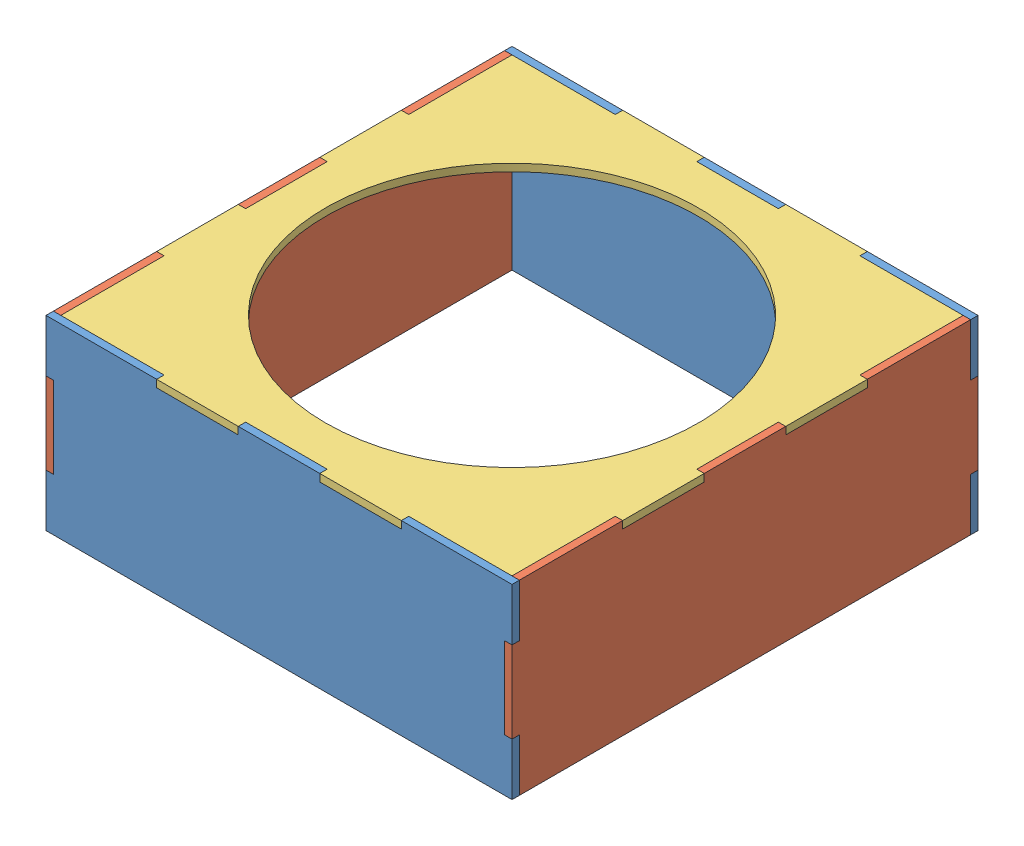
SolidWorks assembly ARM_BOX, configuration Défaut. Lengths in mm.
Overall size (200 80 200).
5 component instances, 3 part files, 13 mates.
Components (placement in the parent):
- BOX_SIDE2-1: BOX_SIDE2 [Défaut] at origin size (200 80 3.17)
- BOX_SIDE2-2: BOX_SIDE2 [Défaut] at (0 0 -196.825) size (200 80 3.17)
- BOX_SIDE1-1: BOX_SIDE1 [Défaut] at (96.825 0 -96.825) x (0 0 -1) z (1 0 0) size (200 80 3.17)
- BOX_SIDE1-2: BOX_SIDE1 [Défaut] at (-96.825 0 -96.825) x (0 0 1) z (-1 0 0) size (200 80 3.17)
- BOX_TOP-1: BOX_TOP [Défaut] at (0 36.825 -96.825) size (200 3.17 200)
Mates (geometry in assembly coordinates):
- Parallèle1: parallel anti-aligned: plane of BOX_SIDE2-1 through (0 0 3.175) normal (0 0 1); plane of BOX_SIDE1-1 through (100 40 -196.825) normal (0 0 -1)
- Coïncidente1: coincident anti-aligned: plane of BOX_SIDE2-1 through (0 0 0) normal (0 0 -1); plane of BOX_SIDE1-1 through (96.825 40 0) normal (0 0 1)
- Coïncidente2: coincident anti-aligned: plane of BOX_SIDE2-1 through (96.825 17.5 0) normal (1 0 0); plane of BOX_SIDE1-1 through (96.825 0 -96.825) normal (-1 0 0)
- Coïncidente3: coincident anti-aligned: plane of BOX_SIDE2-1 through (100 17.5 0) normal (0 -1 0); plane of BOX_SIDE1-1 through (96.825 17.5 3.175) normal (0 1 0)
- Coïncidente4: coincident anti-aligned: plane of BOX_SIDE2-2 through (96.825 17.5 -196.825) normal (1 0 0); plane of BOX_SIDE1-1 through (96.825 0 -96.825) normal (-1 0 0)
- Coïncidente5: coincident anti-aligned: plane of BOX_SIDE2-2 through (0 0 -193.65) normal (0 0 1); plane of BOX_SIDE1-1 through (96.825 -40 -193.65) normal (0 0 -1)
- Coïncidente6: coincident anti-aligned: plane of BOX_SIDE2-2 through (100 -17.5 -196.825) normal (0 1 0); plane of BOX_SIDE1-1 through (96.825 -17.5 -196.825) normal (0 -1 0)
- Coïncidente7: coincident anti-aligned: plane of BOX_SIDE2-2 through (-96.825 17.5 -196.825) normal (-1 0 0); plane of BOX_SIDE1-2 through (-96.825 0 -96.825) normal (1 0 0)
- Coïncidente8: coincident aligned: plane of BOX_SIDE2-2 through (0 0 -196.825) normal (0 0 -1); plane of BOX_SIDE1-2 through (-100 40 -196.825) normal (0 0 -1)
- Coïncidente9: coincident anti-aligned: plane of BOX_SIDE2-2 through (-100 17.5 -196.825) normal (0 -1 0); plane of BOX_SIDE1-2 through (-96.825 17.5 -196.825) normal (0 1 0)
- Coïncidente10: coincident: plane of BOX_SIDE2-2 through (0 0 -193.65) normal (0 0 1); plane of BOX_TOP-1 through (-96.825 170.3855 -193.65) normal (0 0 -1)
- Coïncidente11: coincident: plane of BOX_SIDE1-2 through (-96.825 0 -96.825) normal (1 0 0); plane of BOX_TOP-1 through (-96.825 170.3855 -149.325) normal (-1 0 0)
- Coïncidente12: coincident anti-aligned: plane of BOX_SIDE2-2 through (-17.5 36.825 -196.825) normal (0 1 0); plane of BOX_TOP-1 through (0 170.3855 -96.825) normal (0 -1 0)
